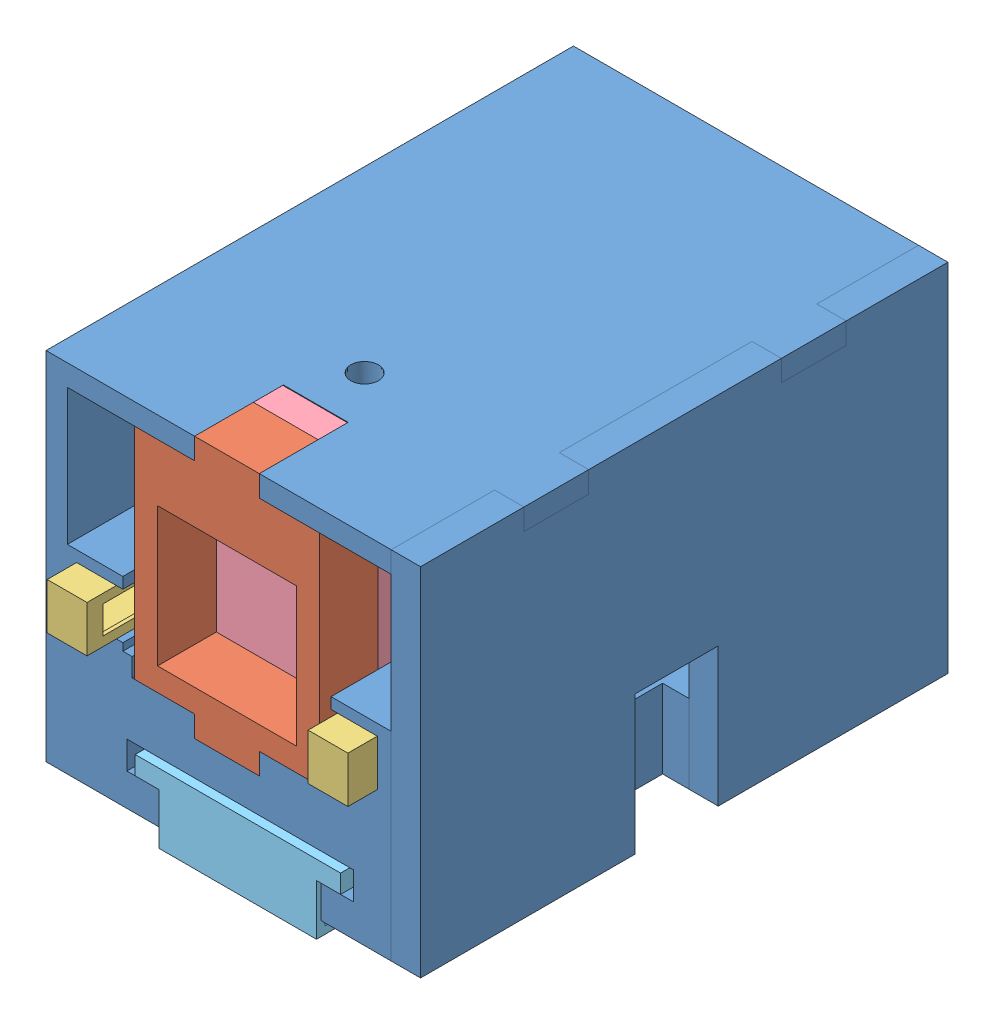
SolidWorks assembly nosepoke_assembly_V3, configuration Food Dispenser . Lengths in mm.
Overall size (40.47 40.5 60.17).
12 component instances, 7 part files, 25 mates.
Components (placement in the parent):
- nosepoke-1: nosepoke [Main Part] at (19.5614 28.6924 45.3731)
- nosepoke_guard-1: nosepoke_guard [Default] at (46.8467 43.0027 96.0231)
- preferenceV2_dispenser_IRAssembly - Copy-1: preferenceV2_dispenser_IRAssembly - Copy [Default] at (23.5614 60.6614 90.0981) x (1 0 0) z (0 -1 0) size (32.5 15.2 5)
  - sparkfunIR_LEDandCase-1: sparkfunIR_LEDandCase [2Pin] at (-11.0025 21.2786 44.4241) x (-1 0 0) z (0 0 -1) size (4.3 15.2 5)
    - sparkfunIR_casing-1: sparkfunIR_casing [Default] at (-40.6525 -5.8286 32.4491) x (1 0 0) z (0 0 -1) size (4.3 15.2 5)
  - sparkfunIR_LEDandCase-2: sparkfunIR_LEDandCase [3Pin] at (42.1025 21.2786 -20.4741) size (4.3 15.2 5)
    - sparkfunIR_casing-1: sparkfunIR_casing [Default] at (-40.6525 -5.8286 32.4491) x (1 0 0) z (0 0 -1) size (4.3 15.2 5)
- nosepoke_guard_backing-1: nosepoke_guard_backing [Default] at (29.1114 43.3864 92.8481)
- nosepoke-3: nosepoke [Side Section ] at (19.5614 28.6924 45.3731)
- nosepoke_magnet_mount-1: nosepoke_magnet_mount [Default] at (29.1914 31.1672 102.3731)
- wall_connector-1: wall_connector [Default] at (25.0014 46.0464 102.3731) (hidden)
- Food dispenser mod-1: Food dispenser mod [Default] at (19.5614 28.6924 102.3731) (hidden)
Mates (geometry in assembly coordinates):
- Coincident19: coincident: plane of nosepoke-1 through (22.8614 51.1864 80.102) normal (1 0 0); plane of preferenceV2_dispenser_IRAssembly - Copy-1/sparkfunIR_LEDandCase-2/sparkfunIR_casing-1 through (22.8614 51.1864 102.3731) normal (-1 0 0)
- Coincident21: coincident: plane of nosepoke-1 through (27.8614 46.1864 80.102) normal (0 1 0); plane of preferenceV2_dispenser_IRAssembly - Copy-1/sparkfunIR_LEDandCase-2/sparkfunIR_casing-1 through (25.0114 46.1864 102.3731) normal (0 -1 0)
- Coincident23: coincident: plane of nosepoke-1 through (55.3614 51.1864 80.102) normal (-1 0 0); plane of preferenceV2_dispenser_IRAssembly - Copy-1/sparkfunIR_LEDandCase-1/sparkfunIR_casing-1 through (55.3614 46.1864 102.3731) normal (1 0 0)
- Coincident30: coincident aligned: plane of nosepoke_guard-1 through (49.1114 60.8864 102.3731) normal (1 0 0); plane of nosepoke_guard_backing-1 through (49.1114 43.3864 96.0231) normal (1 0 0)
- Coincident34: coincident anti-aligned: plane of nosepoke-1 through (60.0364 69.3864 63.3731) normal (0 0 1); plane of nosepoke-3 through (49.4932 69.3864 63.3731) normal (0 0 -1)
- Coincident35: coincident aligned: plane of nosepoke-1 through (21.8614 69.3864 99.1981) normal (0 1 0); plane of nosepoke-3 through (60.0364 69.3864 99.1981) normal (0 1 0)
- Coincident36: coincident aligned: plane of nosepoke-1 through (60.0364 28.6924 45.3731) normal (1 0 0); plane of nosepoke-3 through (60.0364 28.6924 45.3731) normal (1 0 0)
- Coincident42: coincident anti-aligned: plane of nosepoke-1 through (31.7914 34.3864 47.3731) normal (0 1 0); plane of nosepoke_magnet_mount-1 through (31.7914 34.3864 47.3731) normal (0 -1 0)
- Coincident43: coincident anti-aligned: plane of nosepoke-1 through (31.7914 30.8864 47.3731) normal (1 0 0); plane of nosepoke_magnet_mount-1 through (31.7914 28.8864 47.3731) normal (-1 0 0)
- Coincident46: coincident aligned: plane of nosepoke-1 through (19.5614 28.6924 102.3731) normal (0 0 1); plane of nosepoke_guard-1 through (46.8467 43.0027 102.3731) normal (0 0 1)
- Coincident57: coincident anti-aligned: plane of nosepoke_guard-1 through (46.8467 43.0027 102.3731) normal (0 0 1); plane of wall_connector-1 through (25.0014 46.0464 102.3731) normal (0 0 -1)
- Coincident58: coincident aligned: plane of nosepoke_guard-1 through (31.6114 60.8864 102.3731) normal (1 0 0); plane of wall_connector-1 through (31.6114 60.8864 102.3731) normal (1 0 0)
- Coincident61: coincident aligned: plane of nosepoke_guard-1 through (49.1114 43.3864 102.3731) normal (0 -1 0); plane of nosepoke_guard_backing-1 through (29.1114 43.3864 96.0231) normal (0 -1 0)
- Coincident64: coincident anti-aligned: plane of nosepoke-1 through (19.5614 43.3864 45.3731) normal (0 1 0); plane of nosepoke_guard_backing-1 through (29.1114 43.3864 96.0231) normal (0 -1 0)
- Coincident65: coincident aligned: plane of nosepoke_guard-1 through (49.1114 60.8864 102.3731) normal (1 0 0); plane of nosepoke_guard_backing-1 through (49.1114 43.3864 96.0231) normal (1 0 0)
- Coincident67: coincident: line of nosepoke_guard-1 through (31.6114 60.8864 96.0231) axis (1 0 0); plane of nosepoke_guard_backing-1 through (29.1114 43.3864 96.0231) normal (0 0 1)
- Coincident68: coincident aligned: plane of nosepoke-1 through (19.5614 28.6924 102.3731) normal (0 0 1); plane of nosepoke_guard-1 through (46.8467 43.0027 102.3731) normal (0 0 1)
- Distance1: distance = 0.25 mm anti-aligned: plane of nosepoke_guard-1 through (49.1114 60.8864 102.3731) normal (1 0 0); plane of nosepoke-1 through (49.3614 45.3864 92.7731) normal (-1 0 0)
- Coincident70: coincident aligned: plane of nosepoke_guard-1 through (29.1114 60.8864 102.3731) normal (0 -1 0); plane of wall_connector-1 through (31.6114 60.8864 102.3731) normal (0 -1 0)
- InPlace1: in place: plane of ? through (19.5614 28.6924 102.3731) normal (0 0 1); plane of ? through (0 0 102.3731) normal (0 0 1); moOrthogonalPlaneRef_w of ? through (19.5614 28.6924 102.3731) normal (0 0 1); plane of ? through (0 0 102.3731) normal (0 1 0); plane of ? through (19.5614 28.6924 102.3731) normal (0 0 1); plane of ? through (0 0 102.3731) normal (1 0 0); plane of ? through (19.5614 28.6924 102.3731) normal (0 0 1); unknown of Food dispenser mod-1
- Coincident71: coincident aligned: plane of nosepoke-1; plane of Food dispenser mod-1
- Coincident72: coincident aligned: moOrthogonalPlaneRef_w of nosepoke-1 through (19.5614 28.6924 102.3731) normal (0 1 0); plane of Part3^nosepoke_assembly_V3-1 through (19.5614 28.6924 102.3731) normal (0 1 0)
- Coincident73: coincident anti-aligned: moOrthogonalPlaneRef_w of nosepoke-1 through (19.5614 28.6924 102.3731) normal (-1 0 0); plane of Part3^nosepoke_assembly_V3-1 through (19.5614 28.6924 102.3731) normal (1 0 0)
- Coincident71: coincident aligned: plane of wall_connector-1 through (25.0014 46.0464 105.5481) normal (0 0 1); plane of Food dispenser mod-1 through (19.5614 28.6924 105.5481) normal (0 0 1)
- Distance2: distance = 3.175 mm aligned: plane of preferenceV2_dispenser_IRAssembly - Copy-1/sparkfunIR_LEDandCase-2/sparkfunIR_casing-1 through (22.8614 51.1864 105.5481) normal (0 0 1); plane of nosepoke-1 through (19.5614 28.6924 102.3731) normal (0 0 1)
